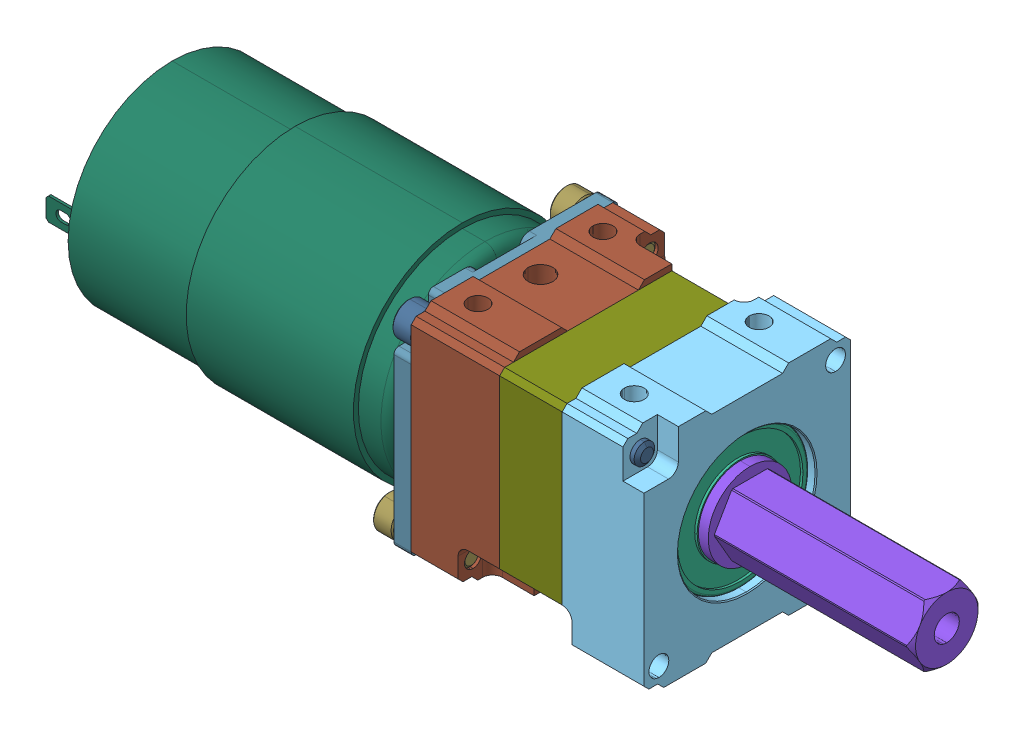
SolidWorks assembly VersaPlanetary v2 Single Stage 10_1 with 775 Series  (1).step, configuration Default. Lengths in mm.
Overall size (166.6 49.04 49.3).
29 component instances, 19 part files, 0 mates.
Components (placement in the parent):
- 217-2820 Rev1_Public.step-1: 217-2820 Rev1_Public.step [Default] at (-4.6546 22.225 0) x (0 -0.456494 0.889726) z (-1 0 0) size (39.22 38.88 17.4)
  - 217-2625-100.step-1: 217-2625-100.step [Default] at origin size (39.22 38.88 12.7)
    - 217-2625-008 Rev1.step-1: 217-2625-008 Rev1.step [Default] at origin size (34.7 34.7 4.7)
    - 217-2625-010 Rev1.step-1: 217-2625-010 Rev1.step [Default] at (0 10.193 3.65) x (0.999813 0.019336 0) z (0 0 1) size (4 4 12)
    - 217-2625-010 Rev1.step-2: 217-2625-010 Rev1.step [Default] at (8.691 -5.3258 3.65) size (4 4 12)
    - 217-2625-010 Rev1.step-3: 217-2625-010 Rev1.step [Default] at (-8.691 -5.3258 3.65) size (4 4 12)
    - 217-2625-005 Rev1_Planet_Revolving_Follower01.step-1: 217-2625-005 Rev1_Planet_Revolving_Follower01.step [Default] at (8.691 -5.3258 6.35) x (0.932816 0.360354 0) z (0 0 1) size (16.89 16.89 8)
    - 217-2625-005 Rev1_Planet_Revolving_Follower01.step-2: 217-2625-005 Rev1_Planet_Revolving_Follower01.step [Default] at (-8.691 -5.3258 6.35) x (-0.932788 -0.360426 0) z (0 0 1) size (16.89 16.89 8)
    - 217-2625-005 Rev1_Planet_Revolving_Follower01.step-3: 217-2625-005 Rev1_Planet_Revolving_Follower01.step [Default] at (0 10.193 6.35) x (0.893583 0.448898 0) z (0 0 1) size (16.89 16.89 8)
  - 217-2625-007 Rev1_Public.step-1: 217-2625-007 Rev1_Public.step [Default] at (0 0 6.7) x (0.992772 0.120019 0) z (0 0 1) size (15.27 15.27 12.7)
- 217-2625-026 Rev1.step-1: 217-2625-026 Rev1.step [Default] at (-6.5 22.225 0) x (0 -1 0) z (-1 0 0) size (44.45 42 18.12)
- 217-2742-001 Rev4.step-1: 217-2742-001 Rev4.step [Default] at (0.2002 22.225 0) x (1 0 0) z (0 -0.092627 0.995701) size (7 28 28)
- 217-2742-001 Rev4.step-2: 217-2742-001 Rev4.step [Default] at (8.2002 22.225 0) size (7 28 28)
- 217-2625-017 Rev1_9714K61.step-1: 217-2625-017 Rev1_9714K61.step [Default] at (7.42 22.3002 -0.342) x (0 0.56703 0.823697) z (0 -0.823697 0.56703) size (28.51 4.98 27.43)
- 217-2625-003 Rev1.step-1: 217-2625-003 Rev1.step [Default] at (7.4478 22.225 0) x (0 -1 0) z (1 0 0) size (17 17 64.11)
- 217-2625-018 Rev1_98541A410.step-1: 217-2625-018 Rev1_98541A410.step [Default] at (-0.7046 22.225 0) x (1 0 0) z (0 -0.017452 0.999848) size (1 19.6 17.4)
- 832-1750-Ring-Gear-Screw_SSA0832-0500ZC.step-1: 832-1750-Ring-Gear-Screw_SSA0832-0500ZC.step [Default] at (-30.7 4.725 -17.5) x (0 0.997447 0.071411) z (0 -0.071411 0.997447) size (6.73 48.51 6.73)
- 832-1750-Ring-Gear-Screw_SSA0832-0500ZC.step-2: 832-1750-Ring-Gear-Screw_SSA0832-0500ZC.step [Default] at (-30.7 39.725 17.5) x (0 0.005929 0.999982) z (0 -0.999982 0.005929) size (6.73 48.51 6.73)
- 217-2625-025 Rev1.step-1: 217-2625-025 Rev1.step [Default] at (-23.2 22.225 0) x (0 -1 0) z (-1 0 0) size (44.45 42 18)
- 217-4649-002 Rev1_SSA0832-0500ZC.step-1: 217-4649-002 Rev1_SSA0832-0500ZC.step [Default] at (-34.2 4.2645 17.9605) x (0 0.33842 -0.940995) z (0 0.940995 0.33842) size (6.73 16.76 6.73)
- 217-4649-002 Rev1_SSA0832-0500ZC.step-2: 217-4649-002 Rev1_SSA0832-0500ZC.step [Default] at (-34.2 40.1855 -17.9605) x (0 -0.308932 -0.951084) z (0 0.951084 -0.308932) size (6.73 16.76 6.73)
- 217-4649-006 Rev1_SSA0004-008BA.step-1: 217-4649-006 Rev1_SSA0004-008BA.step [Default] at (-30.7 22.225 14.5) x (0 0.5 -0.866025) z (0 -0.866025 -0.5) size (7 14 7)
- 217-4649-006 Rev1_SSA0004-008BA.step-2: 217-4649-006 Rev1_SSA0004-008BA.step [Default] at (-30.7 22.225 -14.5) x (0 -1 0) z (0 0 1) size (7 14 7)
- 217-2822-002 Rev4.step-1: 217-2822-002 Rev4.step [Default] at (-32.45 22.225 0) x (0 -1 0) z (-1 0 0) size (42 42 5.3)
- 217-4347-000 Rev1.step-1: 217-4347-000 Rev1.step [Default] at (-34.2 22.225 0) x (-1 0 0) z (0 1 0) size (88 44.3 44.3)
- 217-2816-001 Rev1.step-1: 217-2816-001 Rev1.step [Default] at (-6.35 22.225 0) x (0 -1 0) z (1 0 0) size (42 42 14.51)
- 217-4649-001 Rev1.step-1: 217-4649-001 Rev1.step [Default] at (-20.554 22.225 0) x (0 -1 0) z (1 0 0) size (18 18 13)
- 217-4649-007 Rev1_94105A824.step-1: 217-4649-007 Rev1_94105A824.step [Default] at (-26.029 22.225 -6.7835) x (-0.996104 -0.088191 0) z (0 0 -1) size (4.83 4.83 4.77)
- 217-2625-013 Rev2.step-1: 217-2625-013 Rev2.step [Default] at (-25.2898 22.225 0) x (0 0 1) z (-1 0 0) size (8.01 7.94 7.5)
